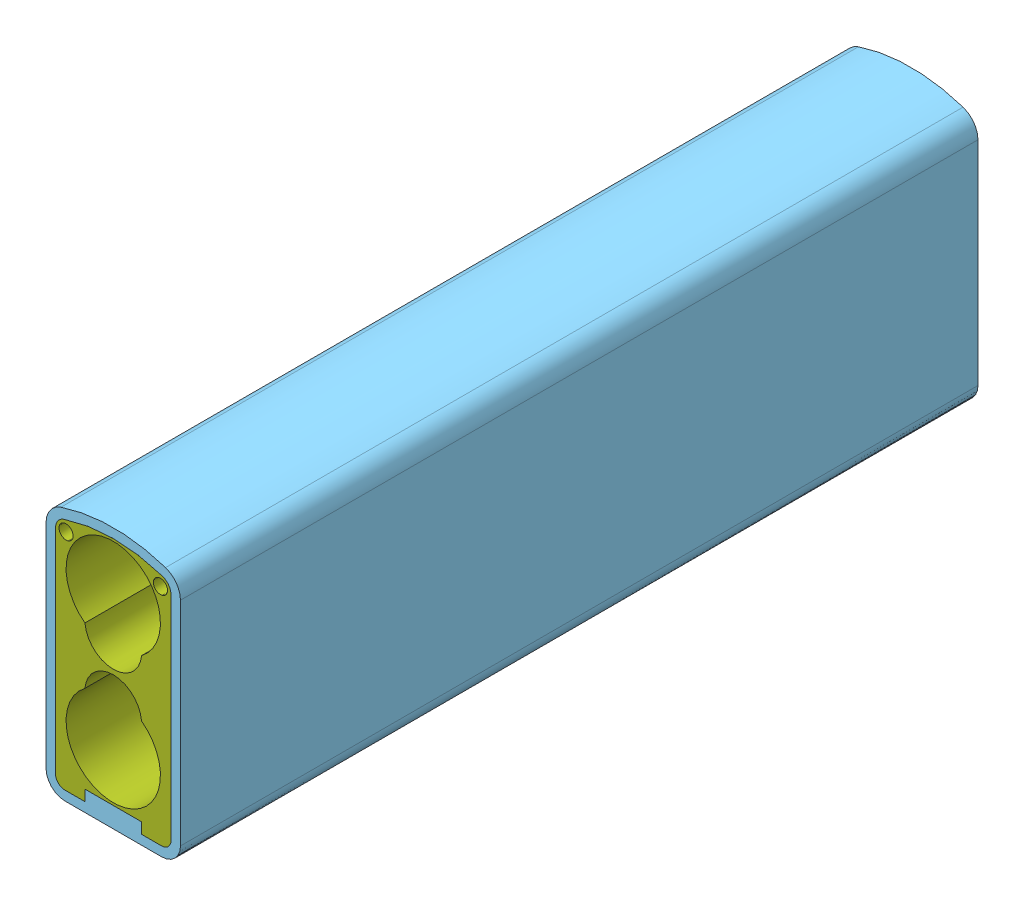
SolidWorks assembly Schulterstuetze, configuration Standard. Lengths in mm.
Overall size (28.5 55.3 169).
11 component instances, 8 part files, 26 mates.
Components (placement in the parent):
- Schulterstuetze Akku_Last-1: Schulterstuetze Akku_Last [Standard] at (-57.1984 -9.8358 -5) size (24.5 51.3 10)
- Schulterstuetze Akku_SecondLast-1: Schulterstuetze Akku_SecondLast [Standard] at (-57.1984 -9.8358 15) size (24.5 51.3 20)
- Schulterstuetze Akku_ThirdLast-2: Schulterstuetze Akku_ThirdLast [Standard] at (-57.1984 -9.8358 50) size (24.5 51.3 35)
- Schulterstuetze Akku_Window-1: Schulterstuetze Akku_Window [Standard] at (-57.1984 -9.8358 84) size (24.5 51.3 34)
- Schulterstütze Tube-1: Schulterstütze Tube [Standard] at (-32.6984 -9.8358 148) x (-1 0 0) z (0 0 -1) size (28.5 55.3 169)
- Schulterstuetze Akku-2: Schulterstuetze Akku [Standard] at (-57.1984 -9.8358 118) size (24.5 51.3 34)
- Schulterstuetze Akku_Short-1: Schulterstuetze Akku_Short [Standard] at (-57.1984 -9.8358 138) size (24.5 51.3 20)
- Kontakt-1: Kontakt [Standard] at (-35.9484 18.6642 -0.6) x (0 0 -1) z (1 0 0) size (20.4 4.8 4.8)
- Kontakt-2: Kontakt [Standard] at (-35.9484 10.6642 -0.6) x (0 0 -1) z (1 0 0) size (20.4 4.8 4.8)
- Kontakt-3: Kontakt [Standard] at (-53.9484 18.6642 -0.6) x (0 0 -1) z (1 0 0) size (20.4 4.8 4.8)
- Kontakt-4: Kontakt [Standard] at (-53.9484 10.6642 -0.6) x (0 0 -1) z (1 0 0) size (20.4 4.8 4.8)
Mates (geometry in assembly coordinates):
- Konzentrisch1: concentric aligned: cylinder of Schulterstuetze Akku_Last-1 through (-44.9484 28.6642 5) axis (0 0 -1) radius 10; cylinder of Schulterstuetze Akku_SecondLast-1 through (-44.9484 28.6642 25) axis (0 0 -1) radius 10
- Konzentrisch2: concentric aligned: cylinder of Schulterstuetze Akku_Last-1 through (-44.9484 0.6642 5) axis (0 0 -1) radius 10; cylinder of Schulterstuetze Akku_SecondLast-1 through (-44.9484 0.6642 25) axis (0 0 -1) radius 10
- Deckungsgleich4: coincident anti-aligned: plane of Schulterstuetze Akku_Last-1 through (-57.1984 -10.1358 5) normal (-1 0 0); plane of Schulterstütze Tube-1 through (-57.1984 -10.1358 -21) normal (1 0 0)
- Abstand1: distance = 16 mm aligned: plane of Schulterstuetze Akku_Last-1 through (-55.1984 -10.1358 -5) normal (0 0 -1); plane of Schulterstütze Tube-1 through (-34.6984 -10.1358 -21) normal (0 0 -1)
- Konzentrisch9: concentric aligned: cylinder of Schulterstuetze Akku_SecondLast-1 through (-44.9484 28.6642 25) axis (0 0 -1) radius 10; cylinder of Schulterstuetze Akku_ThirdLast-2 through (-44.9484 28.6642 60) axis (0 0 -1) radius 10
- Konzentrisch10: concentric aligned: cylinder of Schulterstuetze Akku_SecondLast-1 through (-44.9484 0.6642 25) axis (0 0 -1) radius 10; cylinder of Schulterstuetze Akku_ThirdLast-2 through (-44.9484 0.6642 60) axis (0 0 -1) radius 10
- Deckungsgleich8: coincident anti-aligned: plane of Schulterstuetze Akku_SecondLast-1 through (-55.1984 -10.1358 25) normal (0 0 1); plane of Schulterstuetze Akku_ThirdLast-2 through (-53.4484 11.1642 25) normal (0 0 -1)
- Konzentrisch12: concentric aligned: cylinder of Schulterstuetze Akku-2 through (-44.9484 28.6642 128) axis (0 0 -1) radius 10; cylinder of Schulterstuetze Akku_Short-1 through (-44.9484 28.6642 148) axis (0 0 -1) radius 10
- Konzentrisch13: concentric aligned: cylinder of Schulterstuetze Akku-2 through (-44.9484 0.6642 128) axis (0 0 -1) radius 10; cylinder of Schulterstuetze Akku_Short-1 through (-44.9484 0.6642 148) axis (0 0 -1) radius 10
- Deckungsgleich10: coincident anti-aligned: plane of Schulterstuetze Akku-2 through (-55.1984 -10.1358 128) normal (0 0 1); plane of Schulterstuetze Akku_Short-1 through (-24.6984 14.6642 128) normal (0 0 -1)
- Konzentrisch14: concentric anti-aligned: cylinder of Schulterstuetze Akku_Last-1 through (-35.9484 18.6642 -0.6) axis (0 0 -1) radius 2.4; cylinder of Kontakt-1 through (-35.9484 18.6642 -0.6) axis (0 0 1) radius 2.4
- Konzentrisch15: concentric anti-aligned: cylinder of Schulterstuetze Akku_Last-1 through (-35.9484 10.6642 -0.6) axis (0 0 -1) radius 2.4; cylinder of Kontakt-2 through (-35.9484 10.6642 -0.6) axis (0 0 1) radius 2.4
- Konzentrisch16: concentric anti-aligned: cylinder of Schulterstuetze Akku_Last-1 through (-53.9484 18.6642 -0.6) axis (0 0 -1) radius 2.4; cylinder of Kontakt-3 through (-53.9484 18.6642 -0.6) axis (0 0 1) radius 2.4
- Konzentrisch17: concentric anti-aligned: cylinder of Schulterstuetze Akku_Last-1 through (-53.9484 10.6642 -0.6) axis (0 0 -1) radius 2.4; cylinder of Kontakt-4 through (-53.9484 10.6642 -0.6) axis (0 0 1) radius 2.4
- Deckungsgleich11: coincident anti-aligned: plane of Schulterstuetze Akku_Last-1 through (-35.9484 18.6642 -0.6) normal (0 0 -1); plane of Kontakt-1 through (-38.2484 18.6642 -0.6) normal (0 0 1)
- Deckungsgleich12: coincident anti-aligned: plane of Schulterstuetze Akku_Last-1 through (-35.9484 10.6642 -0.6) normal (0 0 -1); plane of Kontakt-2 through (-38.2484 10.6642 -0.6) normal (0 0 1)
- Deckungsgleich13: coincident anti-aligned: plane of Schulterstuetze Akku_Last-1 through (-53.9484 18.6642 -0.6) normal (0 0 -1); plane of Kontakt-3 through (-56.2484 18.6642 -0.6) normal (0 0 1)
- Deckungsgleich14: coincident anti-aligned: plane of Schulterstuetze Akku_Last-1 through (-53.9484 10.6642 -0.6) normal (0 0 -1); plane of Kontakt-4 through (-56.2484 10.6642 -0.6) normal (0 0 1)
- Deckungsgleich15: coincident anti-aligned: plane of Schulterstuetze Akku_Last-1 through (-55.1984 -10.1358 5) normal (0 0 1); plane of Schulterstuetze Akku_SecondLast-1 through (-53.4484 11.1642 5) normal (0 0 -1)
- Deckungsgleich16: coincident anti-aligned: plane of Schulterstütze Tube-1 through (-32.6984 -10.1358 -21) normal (-1 0 0); plane of Schulterstuetze Akku_Window-1 through (-32.6984 -10.1358 94) normal (1 0 0)
- Deckungsgleich17: coincident anti-aligned: plane of Schulterstütze Tube-1 through (-38.9484 -9.8358 -21) normal (0 1 0); plane of Schulterstuetze Akku_Window-1 through (-50.9484 -9.8358 94) normal (0 -1 0)
- Deckungsgleich18: coincident anti-aligned: plane of Schulterstuetze Akku_ThirdLast-2 through (-55.1984 -10.1358 60) normal (0 0 1); plane of Schulterstuetze Akku_Window-1 through (-24.6984 14.6642 60) normal (0 0 -1)
- Deckungsgleich20: coincident aligned: plane of Schulterstuetze Akku-2 through (-32.6984 -10.1358 128) normal (1 0 0); plane of Schulterstuetze Akku_Window-1 through (-32.6984 -10.1358 94) normal (1 0 0)
- Deckungsgleich21: coincident anti-aligned: plane of Schulterstütze Tube-1 through (-38.9484 -9.8358 -21) normal (0 1 0); plane of Schulterstuetze Akku-2 through (-50.9484 -9.8358 128) normal (0 -1 0)
- Deckungsgleich22: coincident anti-aligned: plane of Schulterstuetze Akku_Window-1 through (-55.1984 -10.1358 94) normal (0 0 1); plane of Schulterstuetze Akku-2 through (-24.6984 14.6642 94) normal (0 0 -1)
- Deckungsgleich23: coincident anti-aligned: plane of Schulterstuetze Akku_ThirdLast-2 through (-50.9484 -9.8358 60) normal (0 -1 0); plane of Schulterstütze Tube-1 through (-38.9484 -9.8358 -21) normal (0 1 0)
